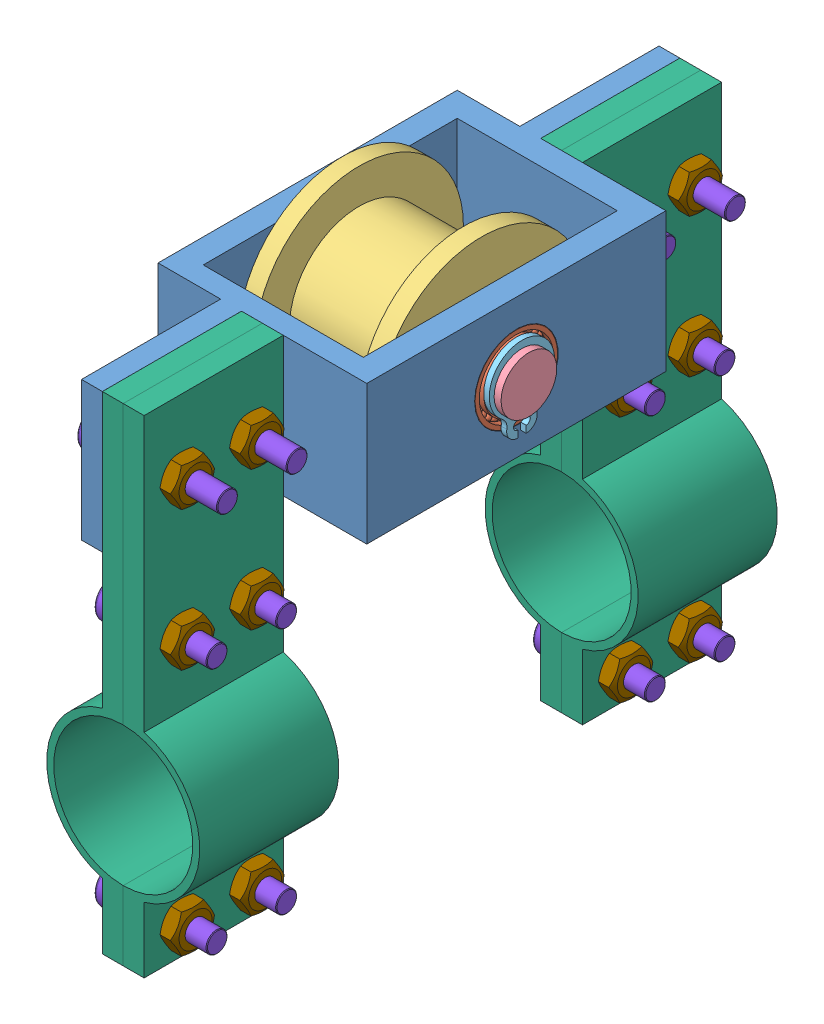
SolidWorks assembly 拉升滑轮, configuration 默认. Lengths in mm.
Overall size (33.6 75 83).
45 component instances, 9 part files, 35 mates.
Components (placement in the parent):
- 拉升滑轮安装架-1: 拉升滑轮安装架 [默认] at (65.3791 0.3041 61.5) size (30 20 83)
- deep groove ball bearings gb-1: deep groove ball bearings gb [Rolling bearings 617-8 GB 276-94] at (11.1291 0.1583 43) size (2.5 12 12)
- deep groove ball bearings gb-2: deep groove ball bearings gb [Rolling bearings 617-8 GB 276-94] at (-16.3709 0.1583 43) size (2.5 12 12)
- 滑轮 - 卷帘-1: 滑轮 - 卷帘 [默认] at (-12.6209 0.1583 43) x (0 -1 0) z (0 0 1) size (30 20 30)
- 滑轮轴-1: 滑轮轴 [默认] at (-2.6209 0.1583 43) x (0 0 -1) z (-1 0 0) size (9.5 9.5 33.6)
- circlips for shaft--type a small gb-2: circlips for shaft--type a small gb [GB_CONNECTING_PIECE_RING_RRA 8] at (12.3791 0.4883 43) x (0 0 1) z (-1 0 0) size (9.38 11.87 0.8)
- circlips for shaft--type a small gb-3: circlips for shaft--type a small gb [GB_CONNECTING_PIECE_RING_RRA 8] at (-17.6209 0.4883 43) x (0 0 -1) z (1 0 0) size (9.38 11.87 0.8)
- 小管夹具-1: 小管夹具 [默认] at (52.9941 -8.7488 11.5) x (-1 0 0) z (0 0 1) size (22 70 20)
  - 夹具-1: 夹具 [默认] at (55.615 31.0944 -10) size (11 70 20)
  - 夹具-2: 夹具 [默认] at (55.615 31.0944 10) x (-1 0 0) z (0 0 -1) size (11 70 20)
  - plain washers-n series-grade a gb-2: plain washers-n series-grade a gb [GB_FASTENER_WASHER_PWNA 3] at (59.115 46.3859 5) x (0 0 -1) z (1 0 0) size (7 7 0.5)
  - plain washers-n series-grade a gb-3: plain washers-n series-grade a gb [GB_FASTENER_WASHER_PWNA 3] at (59.115 46.3859 -5) x (0 0 -1) z (1 0 0) size (7 7 0.5)
  - plain washers-n series-grade a gb-4: plain washers-n series-grade a gb [GB_FASTENER_WASHER_PWNA 3] at (59.115 10.8029 -5) x (0 0 -1) z (1 0 0) size (7 7 0.5)
  - plain washers-n series-grade a gb-5: plain washers-n series-grade a gb [GB_FASTENER_WASHER_PWNA 3] at (59.115 10.8029 5) x (0 0 -1) z (1 0 0) size (7 7 0.5)
  - hexagon socket head cap screws gb-2: hexagon socket head cap screws gb [GB_FASTENER_SCREWS_HSHCS M3X12-N] at (62.115 10.8029 -5) x (-1 0 0) z (0 0.924225 0.381849) size (15 5.5 5.5)
  - hexagon socket head cap screws gb-3: hexagon socket head cap screws gb [GB_FASTENER_SCREWS_HSHCS M3X12-N] at (62.115 10.8029 5) x (-1 0 0) z (0 0.924225 0.381849) size (15 5.5 5.5)
  - hexagon socket head cap screws gb-4: hexagon socket head cap screws gb [GB_FASTENER_SCREWS_HSHCS M3X12-N] at (62.115 46.3859 -5) x (-1 0 0) z (0 0.924225 0.381849) size (15 5.5 5.5)
  - hexagon socket head cap screws gb-5: hexagon socket head cap screws gb [GB_FASTENER_SCREWS_HSHCS M3X12-N] at (62.115 46.3859 5) x (-1 0 0) z (0 0.924225 0.381849) size (15 5.5 5.5)
  - hex nuts, style 1-grades ab gb-2: hex nuts, style 1-grades ab gb [GB_FASTENER_NUT_SNAB1 M3-N] at (50.215 10.8029 -5) x (0 0 1) z (-1 0 0) size (6.35 5.5 2.4)
  - hex nuts, style 1-grades ab gb-3: hex nuts, style 1-grades ab gb [GB_FASTENER_NUT_SNAB1 M3-N] at (50.215 10.8029 5) x (0 0 1) z (-1 0 0) size (6.35 5.5 2.4)
  - hex nuts, style 1-grades ab gb-4: hex nuts, style 1-grades ab gb [GB_FASTENER_NUT_SNAB1 M3-N] at (50.215 46.3859 -5) x (0 0 1) z (-1 0 0) size (6.35 5.5 2.4)
  - hex nuts, style 1-grades ab gb-5: hex nuts, style 1-grades ab gb [GB_FASTENER_NUT_SNAB1 M3-N] at (50.215 46.3859 5) x (0 0 1) z (-1 0 0) size (6.35 5.5 2.4)
- 小管夹具-2: 小管夹具 [默认] at (52.9941 -8.7488 74.5) x (-1 0 0) z (0 0 1) size (22 70 20)
  - 夹具-1: 夹具 [默认] at (55.615 31.0944 -10) size (11 70 20)
  - 夹具-2: 夹具 [默认] at (55.615 31.0944 10) x (-1 0 0) z (0 0 -1) size (11 70 20)
  - plain washers-n series-grade a gb-2: plain washers-n series-grade a gb [GB_FASTENER_WASHER_PWNA 3] at (59.115 46.3859 5) x (0 0 -1) z (1 0 0) size (7 7 0.5)
  - plain washers-n series-grade a gb-3: plain washers-n series-grade a gb [GB_FASTENER_WASHER_PWNA 3] at (59.115 46.3859 -5) x (0 0 -1) z (1 0 0) size (7 7 0.5)
  - plain washers-n series-grade a gb-4: plain washers-n series-grade a gb [GB_FASTENER_WASHER_PWNA 3] at (59.115 10.8029 -5) x (0 0 -1) z (1 0 0) size (7 7 0.5)
  - plain washers-n series-grade a gb-5: plain washers-n series-grade a gb [GB_FASTENER_WASHER_PWNA 3] at (59.115 10.8029 5) x (0 0 -1) z (1 0 0) size (7 7 0.5)
  - hexagon socket head cap screws gb-2: hexagon socket head cap screws gb [GB_FASTENER_SCREWS_HSHCS M3X12-N] at (62.115 10.8029 -5) x (-1 0 0) z (0 0.924225 0.381849) size (15 5.5 5.5)
  - hexagon socket head cap screws gb-3: hexagon socket head cap screws gb [GB_FASTENER_SCREWS_HSHCS M3X12-N] at (62.115 10.8029 5) x (-1 0 0) z (0 0.924225 0.381849) size (15 5.5 5.5)
  - hexagon socket head cap screws gb-4: hexagon socket head cap screws gb [GB_FASTENER_SCREWS_HSHCS M3X12-N] at (62.115 46.3859 -5) x (-1 0 0) z (0 0.924225 0.381849) size (15 5.5 5.5)
  - hexagon socket head cap screws gb-5: hexagon socket head cap screws gb [GB_FASTENER_SCREWS_HSHCS M3X12-N] at (62.115 46.3859 5) x (-1 0 0) z (0 0.924225 0.381849) size (15 5.5 5.5)
  - hex nuts, style 1-grades ab gb-2: hex nuts, style 1-grades ab gb [GB_FASTENER_NUT_SNAB1 M3-N] at (50.215 10.8029 -5) x (0 0 1) z (-1 0 0) size (6.35 5.5 2.4)
  - hex nuts, style 1-grades ab gb-3: hex nuts, style 1-grades ab gb [GB_FASTENER_NUT_SNAB1 M3-N] at (50.215 10.8029 5) x (0 0 1) z (-1 0 0) size (6.35 5.5 2.4)
  - hex nuts, style 1-grades ab gb-4: hex nuts, style 1-grades ab gb [GB_FASTENER_NUT_SNAB1 M3-N] at (50.215 46.3859 -5) x (0 0 1) z (-1 0 0) size (6.35 5.5 2.4)
  - hex nuts, style 1-grades ab gb-5: hex nuts, style 1-grades ab gb [GB_FASTENER_NUT_SNAB1 M3-N] at (50.215 46.3859 5) x (0 0 1) z (-1 0 0) size (6.35 5.5 2.4)
- hexagon socket head cap screws gb-2: hexagon socket head cap screws gb [GB_FASTENER_SCREWS_HSHCS M3X16-N] at (-11.6209 0.4483 6.5) size (19 5.5 5.5)
- hexagon socket head cap screws gb-3: hexagon socket head cap screws gb [GB_FASTENER_SCREWS_HSHCS M3X16-N] at (-11.6209 0.4483 16.5) size (19 5.5 5.5)
- hexagon socket head cap screws gb-4: hexagon socket head cap screws gb [GB_FASTENER_SCREWS_HSHCS M3X16-N] at (-11.6209 0.4483 79.5) size (19 5.5 5.5)
- hexagon socket head cap screws gb-5: hexagon socket head cap screws gb [GB_FASTENER_SCREWS_HSHCS M3X16-N] at (-11.6209 0.4483 69.5) size (19 5.5 5.5)
- hex nuts, style 1-grades ab gb-2: hex nuts, style 1-grades ab gb [GB_FASTENER_NUT_SNAB1 M3-N] at (2.7791 0.4483 6.5) x (0 0 -1) z (1 0 0) size (6.35 5.5 2.4)
- hex nuts, style 1-grades ab gb-3: hex nuts, style 1-grades ab gb [GB_FASTENER_NUT_SNAB1 M3-N] at (2.7791 0.4483 16.5) x (0 0 -1) z (1 0 0) size (6.35 5.5 2.4)
- hex nuts, style 1-grades ab gb-4: hex nuts, style 1-grades ab gb [GB_FASTENER_NUT_SNAB1 M3-N] at (2.7791 0.4483 69.5) x (0 0 -1) z (1 0 0) size (6.35 5.5 2.4)
- hex nuts, style 1-grades ab gb-5: hex nuts, style 1-grades ab gb [GB_FASTENER_NUT_SNAB1 M3-N] at (2.7791 0.4483 79.5) x (0 0 -1) z (1 0 0) size (6.35 5.5 2.4)
Mates (geometry in assembly coordinates):
- 同心1: concentric aligned: cylinder of 拉升滑轮安装架-1 through (20.3791 0.1583 43) axis (-1 0 0) radius 6; cylinder of deep groove ball bearings gb-2 through (-23.3422 0.1583 43) axis (-1 0 0) radius 4
- 重合1: coincident anti-aligned: plane of 拉升滑轮安装架-1 through (-15.1209 0.1583 43) normal (-1 0 0); plane of deep groove ball bearings gb-2 through (-15.1209 6.1583 43) normal (1 0 0)
- 同心2: concentric aligned: cylinder of 拉升滑轮安装架-1 through (20.3791 0.1583 43) axis (-1 0 0) radius 6; cylinder of deep groove ball bearings gb-1 through (4.1578 0.1583 43) axis (-1 0 0) radius 4
- 重合2: coincident anti-aligned: plane of 拉升滑轮安装架-1 through (9.8791 0.1583 43) normal (1 0 0); plane of deep groove ball bearings gb-1 through (9.8791 6.1583 43) normal (-1 0 0)
- 重合3: coincident anti-aligned: plane of 拉升滑轮安装架-1 through (-2.6209 0.3041 61.5) normal (-1 0 0); plane of 滑轮 - 卷帘-1
- 同心3: concentric aligned: cylinder of deep groove ball bearings gb-2 through (-23.3422 0.1583 43) axis (-1 0 0) radius 4; cylinder of 滑轮 - 卷帘-1 through (7.3791 0.1583 43) axis (-1 0 0) radius 4
- 同心4: concentric anti-aligned: cylinder of 滑轮 - 卷帘-1 through (7.3791 0.1583 43) axis (-1 0 0) radius 4; cylinder of 滑轮轴-1 through (-19.4209 0.1583 43) axis (1 0 0) radius 4
- 重合4: coincident anti-aligned: plane of 滑轮 - 卷帘-1 through (7.3791 0.1583 48.5) normal (0 0 -1); plane of 滑轮轴-1 through (-12.6209 -1.3717 48.5) normal (0 0 1)
- 重合5: coincident aligned: plane of deep groove ball bearings gb-1 through (12.3791 4.1583 43) normal (1 0 0); plane of 滑轮轴-1 through (12.3791 -3.8417 43) normal (1 0 0)
- 同心5: concentric anti-aligned: cylinder of 滑轮轴-1 through (16.1791 0.1583 43) axis (1 0 0) radius 3.7; cylinder of circlips for shaft--type a small gb-2 through (13.1791 0.1583 43) axis (-1 0 0) radius 3.7
- 重合6: coincident anti-aligned: plane of 滑轮轴-1 through (12.3791 -3.8417 43) normal (1 0 0); plane of circlips for shaft--type a small gb-2 through (12.3791 -5.0927 42.4) normal (-1 0 0)
- 同心6: concentric anti-aligned: cylinder of 拉升滑轮安装架-1 through (20.3791 0.1583 43) axis (-1 0 0) radius 6; cylinder of circlips for shaft--type a small gb-3 through (-18.4209 0.1583 43) axis (1 0 0) radius 3.7
- 重合7: coincident anti-aligned: plane of 拉升滑轮安装架-1 through (-17.6209 0.3041 64.5) normal (-1 0 0); plane of circlips for shaft--type a small gb-3 through (-17.6209 -5.0927 43.6) normal (1 0 0)
- 同心7: concentric anti-aligned: cylinder of 拉升滑轮安装架-1 through (-8.6209 0.4483 16.5) axis (1 0 0) radius 1.5; cylinder of 小管夹具-1/夹具-2 through (14.3791 0.4483 16.5) axis (-1 0 0) radius 1.5
- 同心8: concentric anti-aligned: cylinder of 拉升滑轮安装架-1 through (-8.6209 0.4483 6.5) axis (1 0 0) radius 1.5; cylinder of 小管夹具-1/夹具-2 through (14.3791 0.4483 6.5) axis (-1 0 0) radius 1.5
- 重合8: coincident anti-aligned: plane of 拉升滑轮安装架-1 through (-5.6209 0.3041 61.5) normal (1 0 0); plane of 小管夹具-1/夹具-2 through (-5.6209 -39.8432 1.5) normal (-1 0 0)
- 同心91: concentric anti-aligned: cylinder of 拉升滑轮安装架-1 through (-8.6209 0.4483 79.5) axis (1 0 0) radius 1.5; cylinder of 小管夹具-2/夹具-2 through (14.3791 0.4483 79.5) axis (-1 0 0) radius 1.5
- 同心101: concentric anti-aligned: cylinder of 拉升滑轮安装架-1 through (-8.6209 0.4483 69.5) axis (1 0 0) radius 1.5; cylinder of 小管夹具-2/夹具-2 through (14.3791 0.4483 69.5) axis (-1 0 0) radius 1.5
- 重合91: coincident anti-aligned: plane of 拉升滑轮安装架-1 through (-5.6209 0.3041 24.5) normal (1 0 0); plane of 小管夹具-2/夹具-2 through (-5.6209 -39.8432 64.5) normal (-1 0 0)
- 同心11: concentric anti-aligned: cylinder of 拉升滑轮安装架-1 through (-8.6209 0.4483 6.5) axis (1 0 0) radius 1.5; cylinder of hexagon socket head cap screws gb-2 through (7.3791 0.4483 6.5) axis (-1 0 0) radius 1.5
- 重合10: coincident anti-aligned: plane of 拉升滑轮安装架-1 through (-8.6209 0.3041 61.5) normal (-1 0 0); plane of hexagon socket head cap screws gb-2 through (-8.6209 0.4483 6.5) normal (1 0 0)
- 同心12: concentric anti-aligned: cylinder of 拉升滑轮安装架-1 through (-8.6209 0.4483 16.5) axis (1 0 0) radius 1.5; cylinder of hexagon socket head cap screws gb-3 through (7.3791 0.4483 16.5) axis (-1 0 0) radius 1.5
- 重合11: coincident anti-aligned: plane of 拉升滑轮安装架-1 through (-8.6209 0.3041 61.5) normal (-1 0 0); plane of hexagon socket head cap screws gb-3 through (-8.6209 0.4483 16.5) normal (1 0 0)
- 同心13: concentric anti-aligned: cylinder of 拉升滑轮安装架-1 through (-8.6209 0.4483 79.5) axis (1 0 0) radius 1.5; cylinder of hexagon socket head cap screws gb-4 through (7.3791 0.4483 79.5) axis (-1 0 0) radius 1.5
- 重合12: coincident anti-aligned: plane of 拉升滑轮安装架-1 through (-8.6209 0.3041 24.5) normal (-1 0 0); plane of hexagon socket head cap screws gb-4 through (-8.6209 0.4483 79.5) normal (1 0 0)
- 同心14: concentric anti-aligned: cylinder of 拉升滑轮安装架-1 through (-8.6209 0.4483 69.5) axis (1 0 0) radius 1.5; cylinder of hexagon socket head cap screws gb-5 through (7.3791 0.4483 69.5) axis (-1 0 0) radius 1.5
- 重合13: coincident anti-aligned: plane of 拉升滑轮安装架-1 through (-8.6209 0.3041 24.5) normal (-1 0 0); plane of hexagon socket head cap screws gb-5 through (-8.6209 0.4483 69.5) normal (1 0 0)
- 同心15: concentric anti-aligned: cylinder of hexagon socket head cap screws gb-2 through (7.3791 0.4483 6.5) axis (-1 0 0) radius 1.5; cone of hex nuts, style 1-grades ab gb-2 through (0.3791 0.4483 6.5) axis (1 0 0)
- 重合14: coincident anti-aligned: plane of 小管夹具-1/夹具-1 through (0.3791 -39.8432 21.5) normal (1 0 0); plane of hex nuts, style 1-grades ab gb-2 through (0.3791 -5.0517 6.5) normal (-1 0 0)
- 同心16: concentric anti-aligned: cylinder of hexagon socket head cap screws gb-3 through (7.3791 0.4483 16.5) axis (-1 0 0) radius 1.5; cone of hex nuts, style 1-grades ab gb-3 through (0.3791 0.4483 16.5) axis (1 0 0)
- 重合15: coincident anti-aligned: plane of 小管夹具-1/夹具-1 through (0.3791 -39.8432 21.5) normal (1 0 0); plane of hex nuts, style 1-grades ab gb-3 through (0.3791 -5.0517 16.5) normal (-1 0 0)
- 同心17: concentric anti-aligned: cylinder of hexagon socket head cap screws gb-5 through (7.3791 0.4483 69.5) axis (-1 0 0) radius 1.5; cone of hex nuts, style 1-grades ab gb-4 through (0.3791 0.4483 69.5) axis (1 0 0)
- 重合16: coincident anti-aligned: plane of 小管夹具-2/夹具-1 through (0.3791 -39.8432 84.5) normal (1 0 0); plane of hex nuts, style 1-grades ab gb-4 through (0.3791 -5.0517 69.5) normal (-1 0 0)
- 同心18: concentric anti-aligned: cylinder of hexagon socket head cap screws gb-4 through (7.3791 0.4483 79.5) axis (-1 0 0) radius 1.5; cone of hex nuts, style 1-grades ab gb-5 through (0.3791 0.4483 79.5) axis (1 0 0)
- 重合17: coincident anti-aligned: plane of 小管夹具-2/夹具-1 through (0.3791 -39.8432 84.5) normal (1 0 0); plane of hex nuts, style 1-grades ab gb-5 through (0.3791 -5.0517 79.5) normal (-1 0 0)
